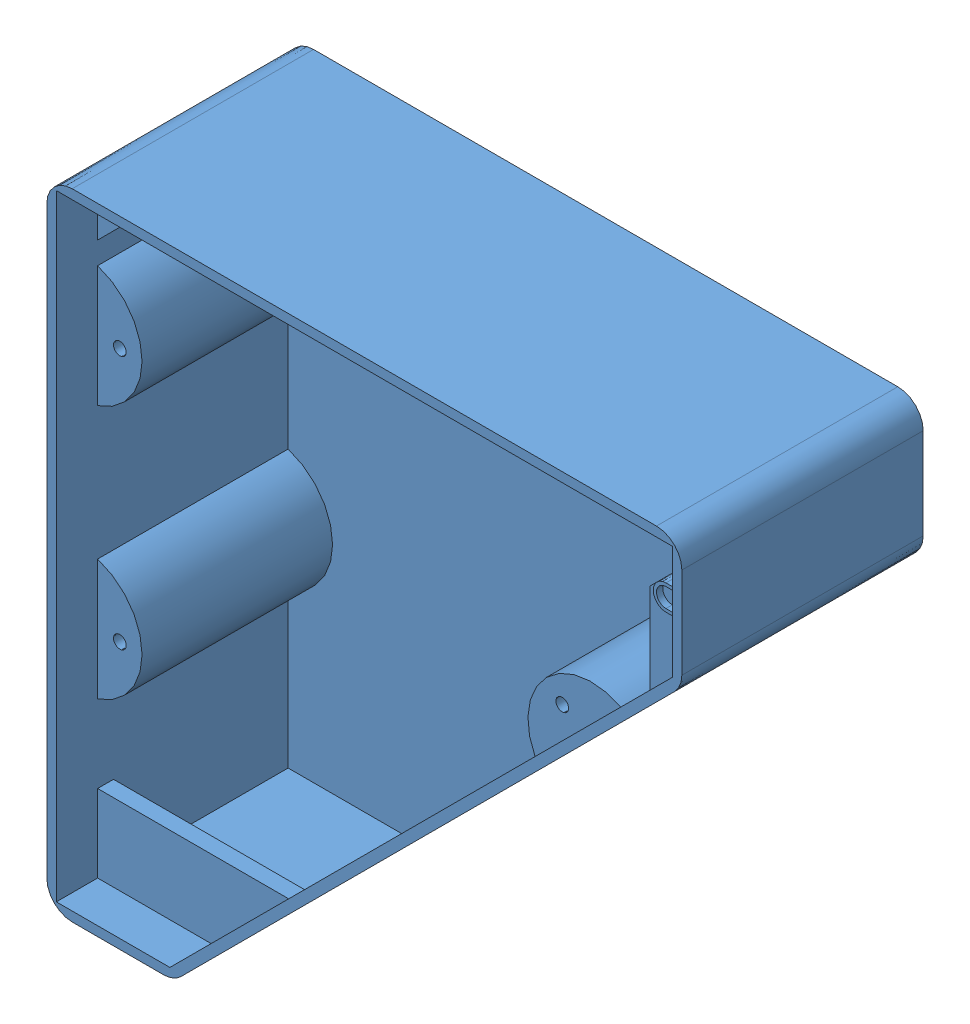
SolidWorks assembly prova2, configuration Default. Lengths in mm.
Overall size (200 200 76).
4 component instances, 4 part files, 7 mates.
Components (placement in the parent):
- base prova.1-1: base prova.1 [Default] at (-169.2516 -99.0096 -39) size (200 200 76)
- layer2.1-1: layer2.1 [Default] at (-166.2516 -92.5884 24) size (183 188 12) (hidden)
- chiave-1: chiave [Default] at (-117.7516 5.4116 -34) x (1 0 0) z (0 -1 0) size (45 88 45) (hidden)
- scree-1: scree [Default] at (-128.0016 -44.5884 -33) x (1 0 0) z (0 -1 0) size (41 65 26) (hidden)
Mates (geometry in assembly coordinates):
- Concentrico1: concentric aligned: cylinder of base prova.1-1 through (-159.2516 51.9116 -6) axis (0 0 1) radius 2; circle of layer2.1-1
- Concentrico2: concentric aligned: circle of base prova.1-1; circle of layer2.1-1
- Coincidente1: coincident anti-aligned: plane of base prova.1-1 through (-172.2516 51.9116 24) normal (0 0 1); plane of layer2.1-1 through (-146.2516 75.4116 24) normal (0 0 -1)
- Concentrico3: concentric anti-aligned: circle of layer2.1-1; cylinder of chiave-1 through (-117.7516 5.4116 54) axis (0 0 -1) radius 13
- Coincidente2: coincident aligned: circle of layer2.1-1; plane of chiave-1 through (-117.7516 5.4116 17) normal (0 0 1)
- Coincidente3: coincident anti-aligned: line of layer2.1-1 through (-145.5016 -32.5884 29) axis (1 0 0); line of scree-1 through (-108.5016 -32.5884 29) axis (-1 0 0)
- Coincidente4: coincident anti-aligned: plane of layer2.1-1 through (-108.5016 -32.5884 24) normal (-1 0 0); plane of scree-1 through (-108.5016 -32.5884 29) normal (1 0 0)
